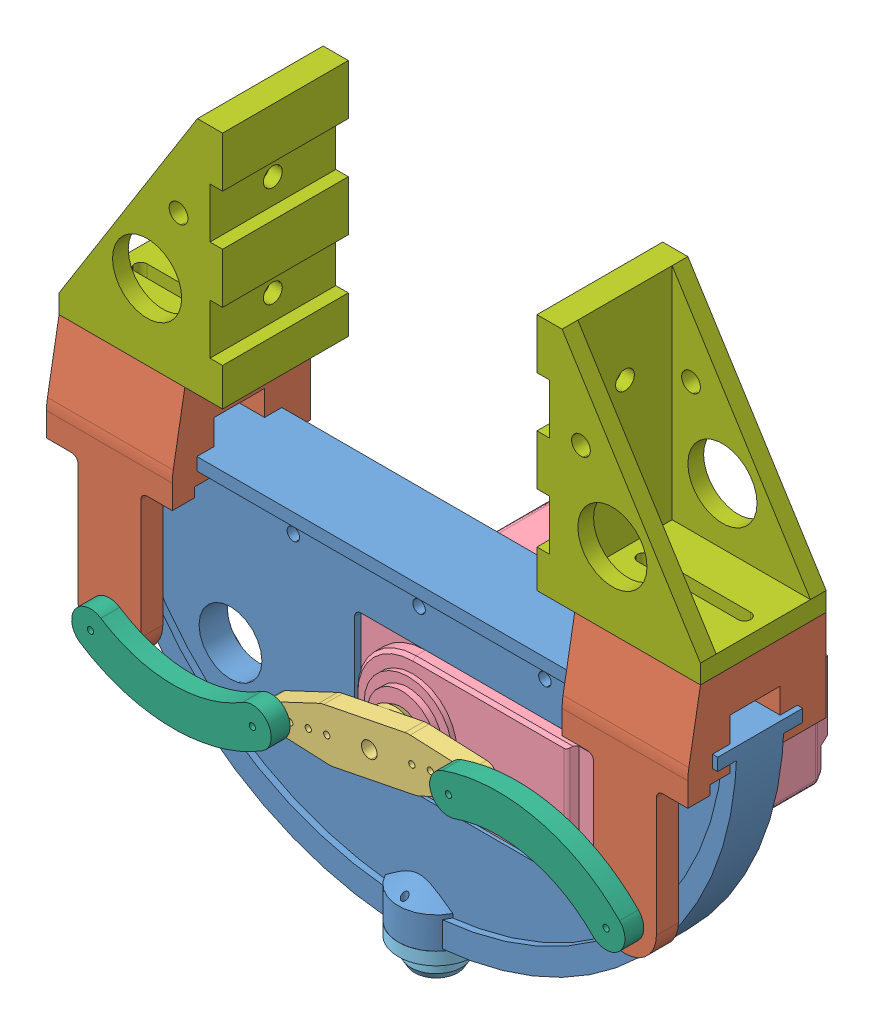
SolidWorks assembly gripper, configuration Default. Lengths in mm.
Overall size (103 105.59 46.92).
10 component instances, 7 part files, 26 mates.
Components (placement in the parent):
- Base-2: Base [Default] at (33.7191 77.8867 75.9336) x (-1 0 0) z (0 0 1) size (103 51.59 13.5)
- Part3 (2)-1: Part3 (2) [Default] at (-17.6178 88.3867 93.3536) x (0 0 -1) z (1 0 0) size (22 41 20)
- Part3 (2)-2: Part3 (2) [Default] at (64.3822 88.3867 93.3536) x (0 0 -1) z (1 0 0) size (22 41 20)
- Estrella-1: Estrella [Predeterminado] at (33.7191 55.1367 93.3536) x (0.195763 -0.980651 0) z (0.980651 0.195763 0) size (8 5 35.3)
- Servo MG966R-1: Servo MG966R [Predeterminado] at (43.8191 55.1367 66.9336) x (-1 0 0) z (0 1 0) size (54.7 41.75 20.5)
- holder-1: holder [Default] at (33.7191 24.2967 82.7263) x (1 0 0) z (0 -1 0) size (12 12 5.5)
- Part4-1: Part4 [Default] at (7.4029 52.9895 93.3536) x (-0.999999 -0.001249 0) z (0 0 1) size (31.74 9.94 3)
- Part4-2: Part4 [Default] at (59.5804 55.0116 93.3536) x (0.977109 -0.21274 0) z (0 0 1) size (31.74 9.94 3)
- Part2-2: Part2 [Default] at (-4.6178 88.3867 71.3536) size (26 38 20)
- Part2-3: Part2 [Default] at (71.3822 88.3867 91.3536) x (-1 0 0) z (0 0 -1) size (26 38 20)
Mates (geometry in assembly coordinates):
- Coincident1: coincident: plane of Base-2 through (85.2191 77.8867 89.4336) normal (0 1 0); plane of Part3 (2)-1 through (-38.4144 77.8867 89.4336) normal (0 -1 0)
- Coincident2: coincident: plane of Base-2 through (33.7191 77.8867 89.4336) normal (0 0 1); plane of Part3 (2)-1 through (-38.4144 75.8867 89.4336) normal (0 0 -1)
- Coincident4: coincident: plane of Base-2 through (33.7191 77.8867 75.9336) normal (0 0 -1); plane of Part3 (2)-2 through (43.5856 77.8867 75.9336) normal (0 0 1)
- Coincident5: coincident: plane of Base-2 through (85.2191 77.8867 89.4336) normal (0 1 0); plane of Part3 (2)-2 through (43.5856 77.8867 89.4336) normal (0 -1 0)
- Coincident12: coincident: plane of Part3 (2)-1 through (2.3822 88.3867 93.3536) normal (0 0 1); plane of Estrella-1 through (33.7191 55.1367 93.3536) normal (0 0 1)
- Coincident14: coincident: plane of Base-2 through (24.4691 44.8867 131.0049) normal (0 1 0); plane of Servo MG966R-1 through (43.8191 44.8867 66.9336) normal (0 -1 0)
- Concentric2: concentric: cone of Estrella-1 through (33.7191 55.1367 88.3536) axis (0 0 -1); cylinder of Servo MG966R-1 through (33.7191 55.1367 91.1836) axis (0 0 -1) radius 3
- Coincident15: coincident: plane of Base-2 through (64.1691 45.8867 131.0049) normal (-1 0 0); plane of Servo MG966R-1 through (64.1691 65.3867 49.4336) normal (1 0 0)
- Coincident17: coincident: plane of Base-2 through (33.7191 79.8867 80.9336) normal (0 0 -1); line of Servo MG966R-1 through (64.1691 55.6367 80.9336) axis (0 -1 0)
- Parallel2: parallel: plane of Base-2 through (33.7191 79.8867 85.4336) normal (0 0 1); plane of Servo MG966R-1 through (64.1691 65.3867 84.4336) normal (0 0 1)
- Coincident18: coincident: plane of Base-2 through (33.7191 26.2967 82.7263) normal (0 -1 0); plane of holder-1 through (33.7191 26.2967 82.7263) normal (0 1 0)
- Concentric3: concentric: cylinder of Base-2 through (33.7191 34.2967 87.7263) axis (0 -1 0) radius 0.5; cylinder of holder-1 through (33.7191 27.7109 87.7263) axis (0 -1 0) radius 0.5
- Concentric4: concentric: cylinder of Base-2 through (33.7191 34.2967 77.7263) axis (0 -1 0) radius 0.5; cylinder of holder-1 through (33.7191 27.7109 77.7263) axis (0 -1 0) radius 0.5
- Concentric5: concentric: circle of Part3 (2)-1; circle of Part4-1
- Concentric6: concentric: circle of Estrella-1; circle of Part4-1
- Coincident21: coincident: plane of Part3 (2)-1 through (2.3822 88.3867 93.3536) normal (0 0 1); plane of Part4-1 through (-1.0387 62.4401 93.3536) normal (0 0 -1)
- Coincident24: coincident: plane of Part3 (2)-2 through (84.3822 88.3867 93.3536) normal (0 0 1); plane of Part4-2 through (65.8045 43.9737 93.3536) normal (0 0 -1)
- Concentric9: concentric: cylinder of Estrella-1 through (49.3111 58.2492 90.3536) axis (0 0 1) radius 0.5; cylinder of Part4-2 through (49.3111 58.2492 96.3536) axis (0 0 -1) radius 0.5
- Concentric10: concentric: cylinder of Part3 (2)-2 through (74.3822 52.3867 88.4394) axis (0 0 1) radius 0.5; cylinder of Part4-2 through (74.3822 52.3867 96.3536) axis (0 0 -1) radius 0.5
- Coincident25: coincident: plane of Part3 (2)-1 through (2.3822 88.3867 93.3536) normal (0 1 0); plane of Part2-2 through (-17.6178 88.3867 91.3536) normal (0 -1 0)
- Coincident27: coincident: plane of Part3 (2)-1 through (2.3822 88.3867 71.3536) normal (0 0 -1); plane of Part2-2 through (-4.6178 88.3867 71.3536) normal (0 0 -1)
- Coincident28: coincident: plane of Part3 (2)-1 through (-17.6178 88.3867 93.3536) normal (-1 0 0); plane of Part2-2 through (-17.6178 88.3867 91.3536) normal (-1 0 0)
- Coincident29: coincident: plane of Part3 (2)-2 through (84.3822 88.3867 93.3536) normal (0 1 0); plane of Part2-3 through (84.3822 88.3867 71.3536) normal (0 -1 0)
- Coincident30: coincident: plane of Part3 (2)-2 through (84.3822 88.3867 71.3536) normal (0 0 -1); plane of Part2-3 through (71.3822 88.3867 71.3536) normal (0 0 -1)
- Coincident31: coincident: plane of Part3 (2)-2 through (84.3822 88.3867 93.3536) normal (1 0 0); plane of Part2-3 through (84.3822 88.3867 71.3536) normal (1 0 0)
- LimitDistance1: limit distance = 50 mm: plane of Part2-2 through (8.3822 88.3867 91.3536) normal (1 0 0); plane of Part2-3 through (58.3822 88.3867 71.3536) normal (-1 0 0)
